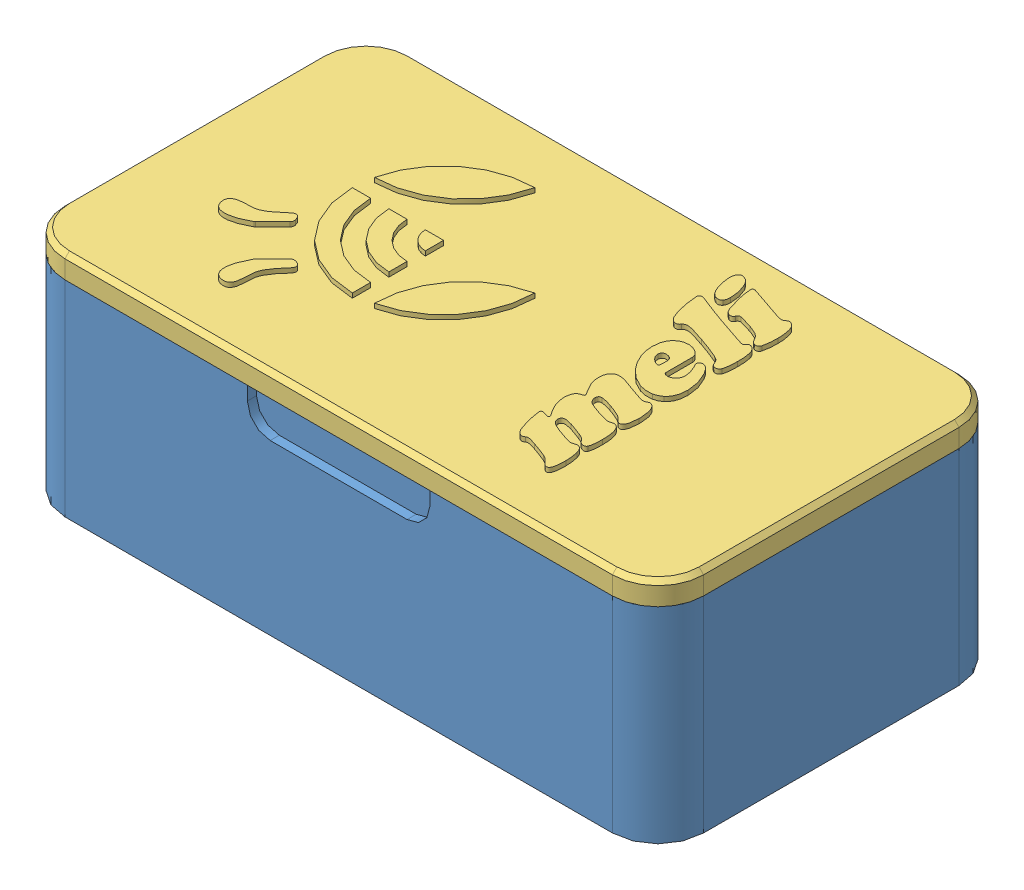
SolidWorks assembly ASSY, configuration Default. Lengths in mm.
Overall size (140 51 76).
3 component instances, 3 part files, 6 mates.
Components (placement in the parent):
- BASE-1: BASE [Default] at (-30.8003 42.2681 156.2875) size (140 45 76)
- PRINT-1: PRINT [Default] at (-20.8003 47.2681 146.2875) size (120 25 56)
- cover-1: cover [Default] at (-30.8003 87.2681 156.2875) size (140 10 76)
Mates (geometry in assembly coordinates):
- Width1: width anti-aligned: plane of PRINT-1 through (-20.8003 72.2681 146.2875) normal (0 0 1); plane of PRINT-1 through (-20.8003 72.2681 90.2875) normal (0 0 -1); plane of BASE-1 through (-20.8003 47.2681 151.2875) normal (0 0 -1); plane of BASE-1 through (99.1997 47.2681 85.2875) normal (0 0 1)
- Width2: width anti-aligned: plane of PRINT-1 through (99.1997 72.2681 146.2875) normal (1 0 0); plane of PRINT-1 through (-20.8003 72.2681 146.2875) normal (-1 0 0); plane of BASE-1 through (104.1997 47.2681 146.2875) normal (-1 0 0); plane of BASE-1 through (-25.8003 47.2681 90.2875) normal (1 0 0)
- Coincident1: coincident anti-aligned: plane of BASE-1 through (99.1997 47.2681 146.2875) normal (0 1 0); plane of PRINT-1 through (-20.8003 47.2681 146.2875) normal (0 -1 0)
- Width3: width anti-aligned: plane of cover-1 through (-30.8003 92.2681 156.2875) normal (0 0 1); plane of cover-1 through (-30.8003 92.2681 80.2875) normal (0 0 -1); plane of BASE-1 through (-30.8003 87.2681 80.2875) normal (0 0 -1); plane of BASE-1 through (-30.8003 87.2681 156.2875) normal (0 0 1)
- Width4: width anti-aligned: plane of cover-1 through (109.1997 92.2681 156.2875) normal (1 0 0); plane of cover-1 through (-30.8003 92.2681 156.2875) normal (-1 0 0); plane of BASE-1 through (-30.8003 87.2681 156.2875) normal (-1 0 0); plane of BASE-1 through (109.1997 87.2681 156.2875) normal (1 0 0)
- Coincident2: coincident anti-aligned: plane of BASE-1 through (-30.8003 87.2681 156.2875) normal (0 1 0); plane of cover-1 through (-30.8003 87.2681 156.2875) normal (0 -1 0)
